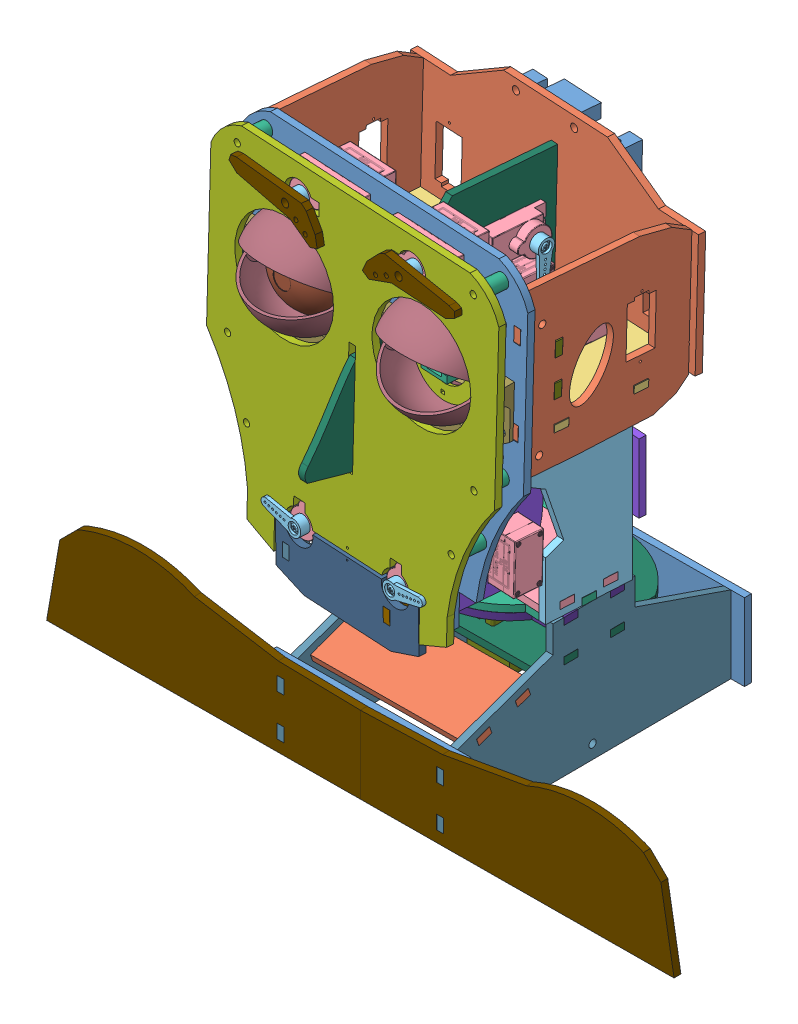
SolidWorks assembly AssemblyFull, configuration Default. Lengths in mm.
Overall size (288.64 237.12 164.6).
100 component instances, 46 part files, 7 mates.
Components (placement in the parent):
- Assembly_skullbox-2: Assembly_skullbox [Default] at (-78.8272 42.8899 40.2473) x (0.99854 0 0.054012) z (-0.053993 0.026286 0.998195) size (140.72 167.86 124.87)
  - faceFrameBack-1: faceFrameBack [Default] at (-18.3406 54.7458 -27.5154) size (140.72 156.7 3.18)
  - skullbox_side-1: skullbox_side [Default] at (-85.5236 10.1688 -63.3929) size (3.18 75.04 78.21)
  - skullbox_bottom-1: skullbox_bottom [Default] at (-18.3406 -15.2312 -64.0914) size (134.47 3.18 65.53)
  - SG90 BODY-1: SG90 BODY [Default] at (-44.9852 -5.3125 -69.5016) x (0 0 1) z (-1 0 0) size (32.36 29.6 12.65)
  - SG90 ARM-1: SG90 ARM [Default] at (-51.2844 1.5836 -75.8008) x (0.999363 0 -0.035696) z (0.035696 0 0.999363) size (19.74 4.23 7.24)
  - SG90 BODY-2: SG90 BODY [Default] at (-34.4188 -5.3125 -64.2438) size (32.36 29.6 12.65)
  - SG90 ARM-2: SG90 ARM [Default] at (-40.718 1.5836 -57.9446) x (0.976821 0 -0.214059) z (0.214059 0 0.976821) size (19.74 4.23 7.24)
  - spacer_#6thread_3_4trlong-1: spacer_#6thread_3_4trlong [93330A443] at (-75.9986 47.1258 -19.5779) x (0.813395 0.581711 0) z (0 0 1) size (6.35 6.35 10.62)
  - spacer_#6thread_3_4trlong-2: spacer_#6thread_3_4trlong [93330A443] at (-68.3786 -59.5542 -19.5779) size (6.35 6.35 10.62)
  - spacer_#6thread_3_4trlong-3: spacer_#6thread_3_4trlong [93330A443] at (39.3174 47.1258 -19.5779) size (6.35 6.35 10.62)
  - spacer_#6thread_3_4trlong-4: spacer_#6thread_3_4trlong [93330A443] at (31.6974 -59.5542 -19.5779) x (-0.161594 -0.986857 0) z (0 0 1) size (6.35 6.35 10.62)
  - faceFrameFront-1: faceFrameFront [Default] at (-18.3406 54.7458 -14.8154) size (140.72 157.48 3.18)
  - spacer_#6thread_3_4trlong-5: spacer_#6thread_3_4trlong [93330A443] at (41.8574 -29.0742 -19.5779) size (6.35 6.35 10.62)
  - spacer_#6thread_3_4trlong-6: spacer_#6thread_3_4trlong [93330A443] at (-78.5386 -29.0742 -19.5779) size (6.35 6.35 10.62)
  - SG90 BODY-4: SG90 BODY [Default] at (-52.3824 35.0825 -17.5967) x (-1 0.000928 0) z (0.000928 1 0) size (32.36 29.6 12.65)
  - skullBoxMandible-3: skullBoxMandible [Default] at (13.4602 -65.9042 -46.5654) size (3.18 63.5 41.33)
  - SG90 BODY-5: SG90 BODY [Default] at (6.7165 -91.99 -42.222) x (0 -1 0) z (0 0 -1) size (32.36 29.6 12.65)
  - SG90 ARM-3: SG90 ARM [Default] at (-0.7384 -85.6908 -48.5212) x (0 0.917715 0.397239) z (0 -0.397239 0.917715) size (19.74 4.23 7.24)
  - jawbone3-1: jawbone3 [Default] at (-0.7384 -85.6908 -48.5212) x (1 0 0) z (0 -0.034208 0.999415) size (3.18 31.5 43.99)
  - jawFront-1: jawFront [Default] at (-18.382 -95.8718 -15.0679) x (1 0 0) z (0 -0.034208 0.999415) size (69.85 26.67 3.17)
  - skullbox_side-2: skullbox_side [Default] at (45.6166 10.4228 -63.3929) size (3.18 75.04 78.21)
  - SG90 BODY-7: SG90 BODY [Default] at (-26.6972 -9.0082 -87.6372) x (0 0 -1) z (0 1 0) size (32.36 29.6 12.65)
  - SG90 ARM-5: SG90 ARM [Default] at (-33.5933 -2.709 -81.338) x (0 -0.999683 0.025167) z (0 -0.025167 -0.999683) size (19.74 4.23 7.24)
  - SG90 BODY-8: SG90 BODY [Default] at (-10.0348 20.1002 -87.6372) x (0 0 -1) z (0 -1 0) size (32.36 29.6 12.65)
  - SG90 ARM-6: SG90 ARM [Default] at (-3.1387 13.801 -81.338) x (0 0.998641 -0.052121) z (0 -0.052121 -0.998641) size (19.74 4.23 7.24)
  - skullBoxMandibleRight-3: skullBoxMandibleRight [Default] at (-53.2656 -65.9042 -46.5654) size (3.18 63.5 41.33)
  - jawCrossBeam-2: jawCrossBeam [Default] at (-23.7889 -100.3419 -40.0004) x (1 0 0) z (0 -0.034208 0.999415) size (52.55 11.43 3.17)
  - mandibleBack-2: mandibleBack [Default] at (-18.3406 -51.2992 -62.3896) size (69.95 34.29 3.18)
  - SG90 BODY-9: SG90 BODY [Default] at (11.5298 -92.5742 -17.5967) x (0 -1 0) z (-1 0 0) size (32.36 29.6 12.65)
  - SG90 ARM-7: SG90 ARM [Default] at (5.2306 -86.275 -10.7006) x (-0.983188 -0.182597 0) z (-0.182597 0.983188 0) size (19.74 4.23 7.24)
  - jawboneRight-1: jawboneRight [Default] at (-50.0144 -85.6908 -48.5212) x (1 0 0) z (0 -0.034208 0.999415) size (3.17 31.94 43.99)
  - SG90 BODY-10: SG90 BODY [Default] at (-35.6126 -92.5742 -17.5967) x (0 -1 0) z (-1 0 0) size (32.36 29.6 12.65)
  - SG90 ARM-8: SG90 ARM [Default] at (-41.9118 -86.275 -10.7006) x (0.976458 -0.215708 0) z (-0.215708 -0.976458 0) size (19.74 4.23 7.24)
  - skullBoxNosePanel-1: skullBoxNosePanel [Default] at (-19.9535 13.3438 -63.5199) size (3.18 90.94 112.09)
  - skullbox_firewall-1: skullbox_firewall [Default] at (-18.2771 6.9938 -43.0602) size (134.37 41.33 3.18)
  - angleBracket_4_40screwThread-1: angleBracket_4_40screwThread [Default] at (41.1335 30.6132 -27.5154) x (0.999994 -0.003567 0) z (0 0 -1) size (8.71 6.35 9.53)
  - angleBracket_4_40screwThread-2: angleBracket_4_40screwThread [Default] at (-77.8147 30.6158 -27.5154) x (-1 0 0) z (0 0 -1) size (8.71 6.35 9.53)
  - angleBracket_4_40screwThread-3: angleBracket_4_40screwThread [Default] at (41.1335 -21.4542 -27.5154) x (1 0 0) z (0 0 -1) size (8.71 6.35 9.53)
  - angleBracket_4_40screwThread-4: angleBracket_4_40screwThread [Default] at (-77.8147 -21.4542 -27.5154) x (-1 0 0) z (0 0 -1) size (8.71 6.35 9.53)
  - angleBracket_4_40screwThread-5: angleBracket_4_40screwThread [Default] at (20.9913 -50.6642 -27.5154) x (-1 0 0) z (0 0 -1) size (8.71 6.35 9.53)
  - angleBracket_4_40screwThread-6: angleBracket_4_40screwThread [Default] at (-57.6725 -50.6642 -27.5154) x (1 0 0) z (0 0 -1) size (8.71 6.35 9.53)
  - SG90 BODY-11: SG90 BODY [Default] at (15.6896 47.5793 -17.5967) x (1 0.000928 0) z (0.000928 -1 0) size (32.36 29.6 12.65)
  - SG90 ARM-9: SG90 ARM [Default] at (-46.0773 41.3759 -10.7006) x (-0.81658 0.577232 0) z (0.577232 0.81658 0) size (19.74 4.23 7.24)
  - SG90 ARM-10: SG90 ARM [Default] at (9.3963 41.2743 -10.7006) x (0.907777 0.419454 0) z (0.419454 -0.907777 0) size (19.74 4.23 7.24)
  - eyebrow-1: eyebrow [Default] at (-51.4817 40.5048 -9.0877) x (0.960868 -0.277008 0) z (0 0 1) size (45.26 13.1 3.17)
  - eyebrow-2: eyebrow [Default] at (14.5528 39.4369 -5.9127) x (-0.995184 -0.098029 0) z (0 0 -1) size (45.26 13.1 3.17)
  - unoKitBoard-1: unoKitBoard [Default] at (-18.3181 17.1284 -102.4454) x (0 1 0) z (0 0 -1) size (72.06 53.59 12.95)
  - skullbox_back-2: skullbox_back [Default] at (-18.3406 10.8038 -102.4454) size (140.72 79.4 3.18)
  - gearLargeB-1: gearLargeB [Default] at (-62.9176 -70.1452 -73.0314) x (0 0 1) z (-1 0 0) size (48.61 57.77 3.18)
  - gearLargeNoTabs-1: gearLargeNoTabs [Default] at (-59.7426 -70.1452 -73.0314) x (0 0 1) z (-1 0 0) size (45.38 54.54 3.17)
  - spacerNeckTilt-1: spacerNeckTilt [Default] at (-59.7426 -42.4092 -45.2954) size (3.17 25.4 25.4)
  - gearLargeNoTabs-2: gearLargeNoTabs [Default] at (-66.0926 -70.1452 -73.0314) x (0 0 1) z (-1 0 0) size (45.38 54.54 3.17)
  - Assembly_eyeWithStraighPullParts-3: Assembly_eyeWithStraighPullParts [Default] at (-52.8322 6.1704 -29.3385) x (-1 0 0) z (0 0 1) size (36.66 36.54 29.79)
    - eyeBracket_straightPull-1: eyeBracket_straightPull [Default] at (-1.0272 -6.7924 0.7563) size (19.05 12.95 22.61)
    - eyeRing_straightPull-1: eyeRing_straightPull [Default] at (-1.1034 -0.1884 5.7083) x (0.999925 0 0.012279) z (-0.012279 -0.002177 0.999922) size (33.02 35.56 7.15)
    - clevisPin_cored-1: clevisPin_cored [Default] at (-1.0272 -8.1259 5.7093) x (0.999925 0 0.012279) z (0 1 0) size (9.65 9.65 18.35)
    - eyeXAxisRod-1: eyeXAxisRod [Default] at (-17.6121 -0.1884 5.5056) x (0.999925 0 0.012279) z (-0.012279 0 0.999925) size (33.02 2.34 2.34)
    - spacer_1_4trlong-1: spacer_1_4trlong [94639A705] at (5.6017 -0.1884 5.7907) x (-0.004447 -0.932122 0.362118) z (-0.999925 0 -0.012279) size (4.76 4.76 6.91)
    - spacer_1_4trlong-2: spacer_1_4trlong [94639A705] at (-7.8085 -0.1884 5.626) x (-0.012279 0 0.999925) z (-0.999925 0 -0.012279) size (4.76 4.76 6.91)
    - eye-1: eye [Default] at (-1.1131 -0.1901 6.502) x (0.999701 0.021124 0.012322) z (-0.012279 -0.002177 0.999922) size (35.76 35.76 12.49)
  - SG90 BODY-12: SG90 BODY [Default] at (-2.5926 -5.3125 -51.747) x (-1 0 0) z (0 0 -1) size (32.36 29.6 12.65)
  - SG90 BODY-13: SG90 BODY [Default] at (20.8008 -5.3125 -69.1714) x (0 0 1) z (-1 0 0) size (32.36 29.6 12.65)
  - SG90 ARM-11: SG90 ARM [Default] at (3.7066 1.5836 -58.0462) x (-0.998428 0 -0.05604) z (0.05604 0 -0.998428) size (19.74 4.23 7.24)
  - SG90 ARM-12: SG90 ARM [Default] at (14.5016 1.5836 -75.4706) x (-0.999964 0 -0.008467) z (0.008467 0 -0.999964) size (19.74 4.23 7.24)
  - spacer_1_4trlong-1: spacer_1_4trlong [94639A705] at (8.4722 6.6128 -23.8353) x (-0.030396 0 0.999538) z (-0.999538 0 -0.030396) size (4.76 4.76 6.91)
  - eyeBracket_straightPull-1: eyeBracket_straightPull [Default] at (15.2509 0.0088 -28.5822) size (19.05 12.95 22.61)
  - eyeRing_straightPull-1: eyeRing_straightPull [Default] at (15.1748 6.6128 -23.6315) x (0.999538 0 0.030396) z (-0.030272 0.090239 0.99546) size (33.02 35.56 7.15)
  - clevisPin_cored-1: clevisPin_cored [Default] at (15.2509 -1.3247 -23.6292) x (0.999538 0 0.030396) z (0 1 0) size (9.65 9.65 18.35)
  - eyeXAxisRod-1: eyeXAxisRod [Default] at (-1.3276 6.6128 -24.1334) x (0.999538 0 0.030396) z (-0.030396 0 0.999538) size (33.02 2.34 2.34)
  - spacer_1_4trlong-2: spacer_1_4trlong [94639A705] at (21.8773 6.6128 -23.4277) x (-0.030396 0 0.999538) z (-0.999538 0 -0.030396) size (4.76 4.76 6.91)
  - eye-1: eye [Default] at (15.1507 6.6844 -22.8414) x (-0.843364 -0.536849 0.023019) z (-0.030272 0.090239 0.99546) size (35.76 35.76 12.49) (hidden)
  - Assembly_Eyelid_StraightPullParts-1: Assembly_Eyelid_StraightPullParts [Default] at (-51.0341 -8.3385 -21.5988) size (62.38 64.85 38.25)
    - eyeLidMount_B-1: eyeLidMount_B [Default] at (-0.8344 -17.1797 -2.7416) x (-1 0 0) z (0 0 1) size (62.38 36.2 5.33)
    - eyelidA-2: eyelidA [Default] at (-1.4136 14.8243 0.4334) x (0 0.463125 0.886293) z (-1 0 0) size (27.73 27.4 48.41)
    - eyelidA-3: eyelidA [Default] at (-1.1646 14.8243 0.4334) x (0 -0.332285 0.943179) z (1 0 0) size (27.73 27.4 48.41)
  - eyeLidMount_B-1: eyeLidMount_B [Default] at (15.1874 -25.5182 -24.3404) x (-1 0 0) z (0 0 1) size (62.38 36.2 5.33)
  - eyelidA-1: eyelidA [Default] at (14.6083 6.4858 -21.1654) x (0 0.456477 0.889735) z (-1 0 0) size (27.73 27.4 48.41)
  - eyelidA-2: eyelidA [Default] at (14.8572 6.4858 -21.1654) x (0 -0.518383 0.855148) z (1 0 0) size (27.73 27.4 48.41)
- assemblyRotateBase-1: assemblyRotateBase [Default] at (-119.5239 -107.7802 -45.861) x (-0.99998 0 0.006338) z (-0.006338 0 -0.99998) size (287.78 63.55 136.53)
  - rotateBaseSides-1: rotateBaseSides [Default] at (8.1657 0.2779 -4.4977) size (3.18 63.5 136.53)
  - rotateBaseSides-2: rotateBaseSides [Default] at (-65.1133 0.2779 -4.4977) size (3.18 63.5 136.53)
  - rotateBaseServoPlate-1: rotateBaseServoPlate [Default] at (-26.8863 13.0541 -4.4977) size (76.56 3.18 76.2)
  - Standard ServoB-1: Standard ServoB [Default] at (-25.2626 -10.8409 6.7516) x (0 0 -1) z (1 0 0) size (55.73 42.63 19.57)
  - thrustBearingBottom-1: thrustBearingBottom [Default] at (-26.8863 28.9037 -4.4977) size (76.56 3.18 68.58)
  - shoulderFront-1: shoulderFront [Default] at (-26.8355 -31.4721 -74.3477) size (143.94 48.97 3.17)
  - shoulderFront-2: shoulderFront [Default] at (-26.9371 -31.4721 -71.1727) x (-1 0 0) z (0 0 -1) size (143.94 48.97 3.17)
  - chestWall-1: chestWall [Default] at (-26.8355 -13.6921 -71.1727) size (89.15 35.56 3.17)
  - chestWall-2: chestWall [Default] at (-26.8355 -13.6921 59.0023) size (89.15 35.56 3.17)
  - neckCover-1: neckCover [Default] at (-26.8863 4.9145 -46.0534) x (1 0 0) z (0 0.328989 0.944334) size (76.56 3.18 31.75)
- AssemblyNeckTiltColumn-4: AssemblyNeckTiltColumn [Default] at (-122.0432 -18.8777 -54.5662) x (-0.99854 0 -0.054012) z (0.054012 0 -0.99854) size (89.52 84.33 78.24)
  - neckTiltColumn-1: neckTiltColumn [Default] at (4.9917 -2.1149 -1.1972) size (3.18 82.55 66.23)
  - neckTiltColumnBottom-1: neckTiltColumnBottom [Default] at (-30.0603 -53.6488 -11.3459) size (76.56 3.18 38.1)
  - Standard ServoB-1: Standard ServoB [Default] at (-24.5383 -16.1199 -10.0251) x (0 1 0) z (0 0 -1) size (55.73 42.63 19.57)
  - neckTiltColumnLeft-1: neckTiltColumnLeft [Default] at (-68.2873 -2.0641 -1.1972) size (3.18 82.55 66.23)
  - thrustBearingTop-2: thrustBearingTop [Default] at (-30.0603 -56.8238 -11.3459) size (76.56 3.18 68.58)
  - servoHorn4Arm_standardSize-1: servoHorn4Arm_standardSize [Default] at (-30.0603 -55.6808 -11.3459) x (0.999674 0 0.025542) z (0.025542 0 -0.999674) size (37.1 4.83 37.1)
  - neckTiltColumnBack-1: neckTiltColumnBack [Default] at (-30.0603 -14.6598 7.7041) size (82.8 31.75 3.17)
- gearSmall-1: gearSmall [Default] at (-141.4583 -44.4557 -26.6072) x (0.054012 0.002231 -0.998538) z (0.99854 0 0.054012) size (40.04 41.03 3.17)
- tiltAxle-1: tiltAxle [Default] at (-155.1366 -0.6445 -8.1099) x (0.99854 0 0.054012) z (-0.048908 0.424328 0.904187) size (101.6 6.35 6.35)
Mates (geometry in assembly coordinates):
- Concentric4: concentric anti-aligned: cylinder of Assembly_skullbox-2/skullBoxMandibleRight-3 through (-129.6297 -0.6953 -6.7302) axis (0.99854 0 0.054012) radius 3.2385; cylinder of AssemblyNeckTiltColumn-4/neckTiltColumn-1 through (-129.6296 -0.6953 -6.7302) axis (-0.99854 0 -0.054012) radius 3.048
- Concentric5: concentric aligned: cylinder of assemblyRotateBase-1/Standard ServoB-1 through (-92.6395 -83.0211 -41.6132) axis (0 1 0) radius 1.27; cylinder of AssemblyNeckTiltColumn-4/servoHorn4Arm_standardSize-1 through (-92.6395 -77.3525 -41.6132) axis (0 1 0) radius 2.794
- Coincident5: coincident anti-aligned: plane of assemblyRotateBase-1/thrustBearingBottom-1 through (-127.5401 -75.7015 -22.262) normal (0 1 0); plane of AssemblyNeckTiltColumn-4/thrustBearingTop-2 through (-128.6693 -75.7015 -24.4843) normal (0 -1 0)
- Coincident12: coincident anti-aligned: plane of Assembly_skullbox-2/skullBoxMandibleRight-3 through (-128.5208 7.0227 -27.2302) normal (-0.99854 0 -0.054012); plane of AssemblyNeckTiltColumn-4/neckTiltColumn-1 through (-129.1911 -0.6953 -14.8366) normal (0.99854 0 0.054012)
- Concentric6: concentric aligned: cylinder of AssemblyNeckTiltColumn-4/Standard ServoB-1 through (-133.5441 -23.8279 -46.7451) axis (-0.99854 0 -0.054012) radius 1.27; cylinder of gearSmall-1 through (-137.1787 -23.8279 -46.9417) axis (-0.99854 0 -0.054012) radius 4.826
- Coincident13: coincident anti-aligned: plane of AssemblyNeckTiltColumn-4/Standard ServoB-1 through (-137.1787 -23.8279 -46.9417) normal (-0.99854 0 -0.054012); plane of gearSmall-1 through (-137.9797 -14.9633 -32.134) normal (0.99854 0 0.054012)
- Concentric7: concentric aligned: cylinder of AssemblyNeckTiltColumn-4/neckTiltColumnLeft-1 through (-56.4576 -0.6445 -2.7723) axis (-0.99854 0 -0.054012) radius 3.048; cylinder of tiltAxle-1 through (-53.6849 -0.6445 -2.6223) axis (-0.99854 0 -0.054012) radius 3.175
